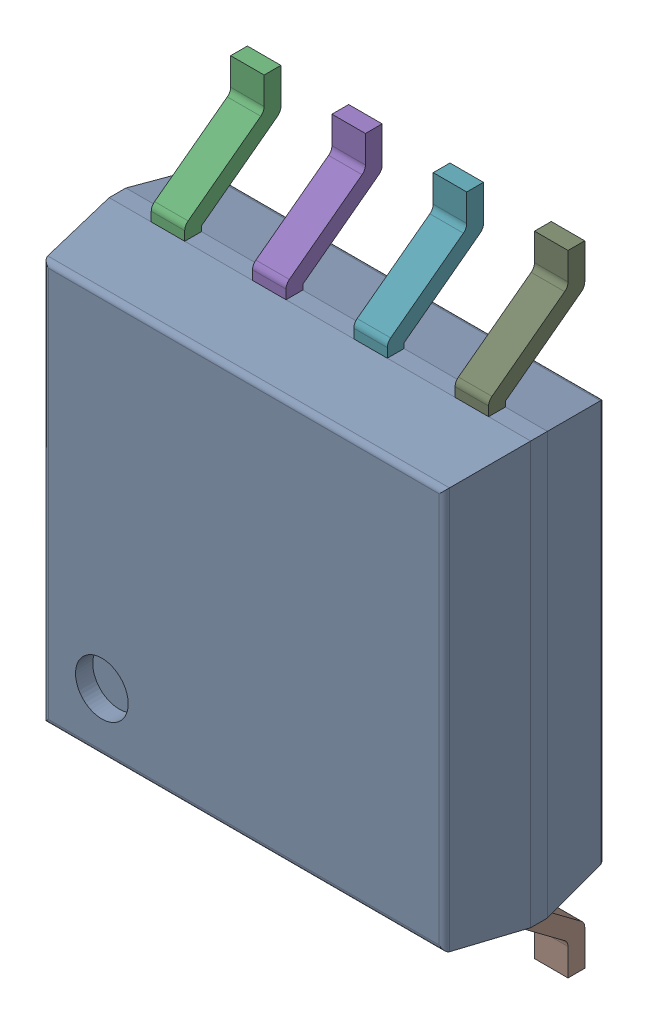
SolidWorks assembly IC55_1.step, configuration Default. Lengths in mm.
Overall size (5.29 7.9 2.16).
3 component instances, 2 part files, 0 mates.
Components (placement in the parent):
- 6348792448_1.step-11: 6348792448_1.step [Default] at (434.166 277.338 0) x (0 1 0) z (0 0 1) size (7.9 5.29 2.16)
  - Body-12_1.step-21: Body-12_1.step [Default] at origin size (5.29 5.29 2.01)
  - PinsArrayLR-13_1.step-21: PinsArrayLR-13_1.step [Default] at origin size (7.9 4.23 1.21)
